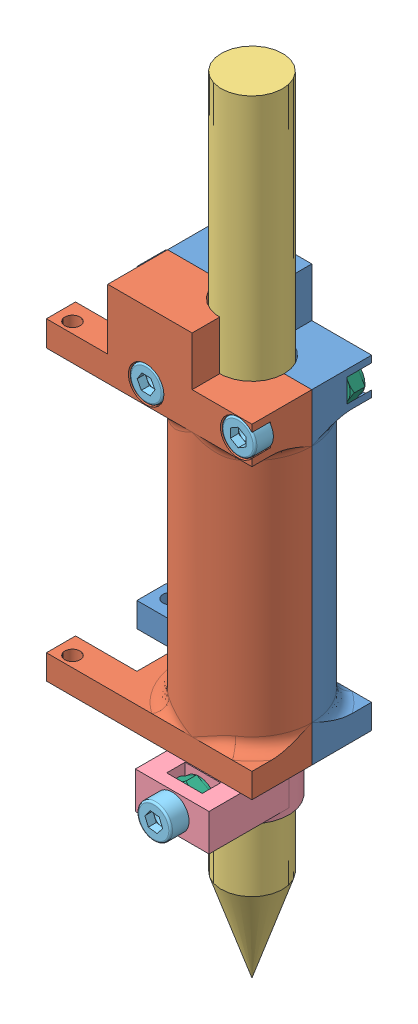
SolidWorks assembly ass_support_stylo_ON, configuration Défaut. Lengths in mm.
Overall size (35.22 128 25.75).
10 component instances, 6 part files, 21 mates.
Components (placement in the parent):
- support_stylo_mot1_ON-1: support_stylo_mot1_ON [Défaut] at (-9.655 27.9226 55.8974) size (33.99 61 10.21)
- support_stylo_mot2_ON-1: support_stylo_mot2_ON [Défaut] at (-9.655 27.9226 75.3974) x (-1 0 0) z (0 0 -1) size (33.5 61 9.75)
- stylo-1: stylo [Défaut] at (-9.655 64.9227 65.6474) x (-0.739372 0 0.673298) z (0 -1 0) size (10 10 128)
- support_stylo-1: support_stylo [Défaut] at (-9.655 -17.0773 65.6474) x (0 0 -1) z (0 1 0) size (19 15 52)
- socket head cap screw 4762_din-1: socket head cap screw 4762_din [EN ISO 4762 M3 x 16 - 16N] at (-17.155 21.8297 75.3974) x (0 0 -1) z (-0.845418 0.534105 0) size (19 5.5 5.5)
- socket head cap screw 4762_din-2: socket head cap screw 4762_din [EN ISO 4762 M3 x 16 - 16N] at (-2.155 21.8297 75.3974) x (0 0 -1) z (1 0 0) size (19 5.5 5.5)
- hex nut style 1 gradeab_din-1: hex nut style 1 gradeab_din [Hexagon Nut ISO 4032 - M3 - W - N] at (-17.155 21.8297 59.8974) x (0.866025 0.5 0) z (0 0 1) size (5.5 6.35 2.4)
- hex nut style 1 gradeab_din-2: hex nut style 1 gradeab_din [Hexagon Nut ISO 4032 - M3 - W - N] at (-2.155 21.8297 59.8974) x (0.866025 0.5 0) z (0 0 1) size (5.5 6.35 2.4)
- socket head cap screw 4762_din-3: socket head cap screw 4762_din [EN ISO 4762 M3 x 10 - 10N] at (-9.655 -33.0773 81.6474) x (0 0 -1) z (0.923728 0.383049 0) size (13 5.5 5.5)
- hex nut style 1 gradeab_din-3: hex nut style 1 gradeab_din [Hexagon Nut ISO 4032 - M3 - W - N] at (-9.655 -33.0773 76.6474) size (5.5 6.35 2.4)
Mates (geometry in assembly coordinates):
- Coaxiale1: concentric anti-aligned: cylinder of stylo-1 through (-9.655 -63.0773 65.6474) axis (0 1 0) radius 5; cylinder of support_stylo-1 through (-9.655 -15.0773 65.6474) axis (0 -1 0) radius 5
- Distance1: distance = 50 mm aligned: plane of support_stylo-1 through (-9.7692 14.9227 65.6474) normal (0 1 0); plane of stylo-1 through (-9.655 64.9227 65.6474) normal (0 1 0)
- Coaxiale2: concentric aligned: cylinder of support_stylo_mot1_ON-1 through (-9.655 -26.1703 65.6474) axis (0 1 0) radius 7.75; cylinder of support_stylo-1 through (-9.655 -37.0773 65.6474) axis (0 1 0) radius 6
- Coaxiale3: concentric anti-aligned: cylinder of support_stylo_mot1_ON-1 through (-17.155 21.8297 55.8974) axis (0 0 1) radius 1.75; cylinder of support_stylo_mot2_ON-1 through (-17.155 21.8297 75.3974) axis (0 0 -1) radius 1.75
- Coaxiale4: concentric anti-aligned: cylinder of support_stylo_mot1_ON-1 through (-2.155 21.8297 55.8974) axis (0 0 1) radius 1.75; cylinder of support_stylo_mot2_ON-1 through (-2.155 21.8297 75.3974) axis (0 0 -1) radius 1.75
- Coïncidente2: coincident anti-aligned: plane of support_stylo_mot1_ON-1 through (-1.905 -26.1703 65.6474) normal (0 0 1); plane of support_stylo_mot2_ON-1 through (-17.405 -26.1703 65.6474) normal (0 0 -1)
- Coaxiale5: concentric anti-aligned: cylinder of support_stylo_mot2_ON-1 through (-2.155 21.8297 75.3974) axis (0 0 -1) radius 1.75; cylinder of socket head cap screw 4762_din-2 through (-2.155 21.8297 107.1474) axis (0 0 1) radius 1.5
- Coïncidente3: coincident anti-aligned: plane of support_stylo_mot2_ON-1 through (-2.155 21.8297 72.3974) normal (0 0 1); plane of socket head cap screw 4762_din-2 through (-2.155 24.5797 72.3974) normal (0 0 -1)
- Coaxiale6: concentric anti-aligned: cylinder of support_stylo_mot2_ON-1 through (-17.155 21.8297 75.3974) axis (0 0 -1) radius 1.75; cylinder of socket head cap screw 4762_din-1 through (-17.155 21.8297 107.1474) axis (0 0 1) radius 1.5
- Coïncidente4: coincident anti-aligned: plane of support_stylo_mot2_ON-1 through (-17.155 21.8297 72.3974) normal (0 0 1); plane of socket head cap screw 4762_din-1 through (-18.6237 19.5048 72.3974) normal (0 0 -1)
- Coaxiale7: concentric aligned: cylinder of socket head cap screw 4762_din-2 through (-2.155 21.8297 107.1474) axis (0 0 1) radius 1.5; cylinder of hex nut style 1 gradeab_din-2 through (-2.155 21.8297 57.4974) axis (0 0 1) radius 1.25
- Coaxiale8: concentric aligned: cylinder of hex nut style 1 gradeab_din-1 through (-17.155 21.8297 57.4974) axis (0 0 1) radius 1.25; cylinder of socket head cap screw 4762_din-1 through (-17.155 21.8297 107.1474) axis (0 0 1) radius 1.5
- Parallèle1: parallel aligned: plane of support_stylo_mot1_ON-1 through (-3.8293 18.9297 59.8974) normal (0.866025 0.5 0); plane of hex nut style 1 gradeab_din-2 through (-0.5672 24.5797 57.4974) normal (0.866025 0.5 0)
- Parallèle2: parallel aligned: plane of support_stylo_mot1_ON-1 through (-18.8293 18.9297 59.8974) normal (0.866025 0.5 0); plane of hex nut style 1 gradeab_din-1 through (-15.5672 24.5797 57.4974) normal (0.866025 0.5 0)
- Coïncidente7: coincident anti-aligned: plane of support_stylo_mot1_ON-1 through (-9.655 27.9226 59.8974) normal (0 0 -1); plane of hex nut style 1 gradeab_din-2 through (-3.7427 24.5797 59.8974) normal (0 0 1)
- Coïncidente8: coincident anti-aligned: plane of support_stylo_mot1_ON-1 through (-9.655 27.9226 59.8974) normal (0 0 -1); plane of hex nut style 1 gradeab_din-1 through (-18.7427 24.5797 59.8974) normal (0 0 1)
- Parallèle3: parallel aligned: plane of support_stylo_mot2_ON-1 through (-23.405 -24.1703 75.3974) normal (-1 0 0); plane of support_stylo-1 through (-15.655 -36.0773 65.6474) normal (-1 0 0)
- Coaxiale9: concentric aligned: cylinder of support_stylo-1 through (-9.655 -33.0773 62.6474) axis (0 0 1) radius 1.75; cylinder of hex nut style 1 gradeab_din-3 through (-9.655 -33.0773 74.2474) axis (0 0 1) radius 1.25
- Coïncidente10: coincident anti-aligned: plane of support_stylo-1 through (-12.555 -23.5473 76.6474) normal (0 0 -1); plane of hex nut style 1 gradeab_din-3 through (-9.655 -29.9018 76.6474) normal (0 0 1)
- Coaxiale10: concentric aligned: cylinder of support_stylo-1 through (-9.655 -33.0773 62.6474) axis (0 0 1) radius 1.75; cylinder of socket head cap screw 4762_din-3 through (-9.655 -33.0773 113.3974) axis (0 0 1) radius 1.5
- Coïncidente11: coincident anti-aligned: plane of support_stylo-1 through (-15.655 -36.0773 78.6474) normal (0 0 1); plane of socket head cap screw 4762_din-3 through (-10.7083 -30.537 78.6474) normal (0 0 -1)
